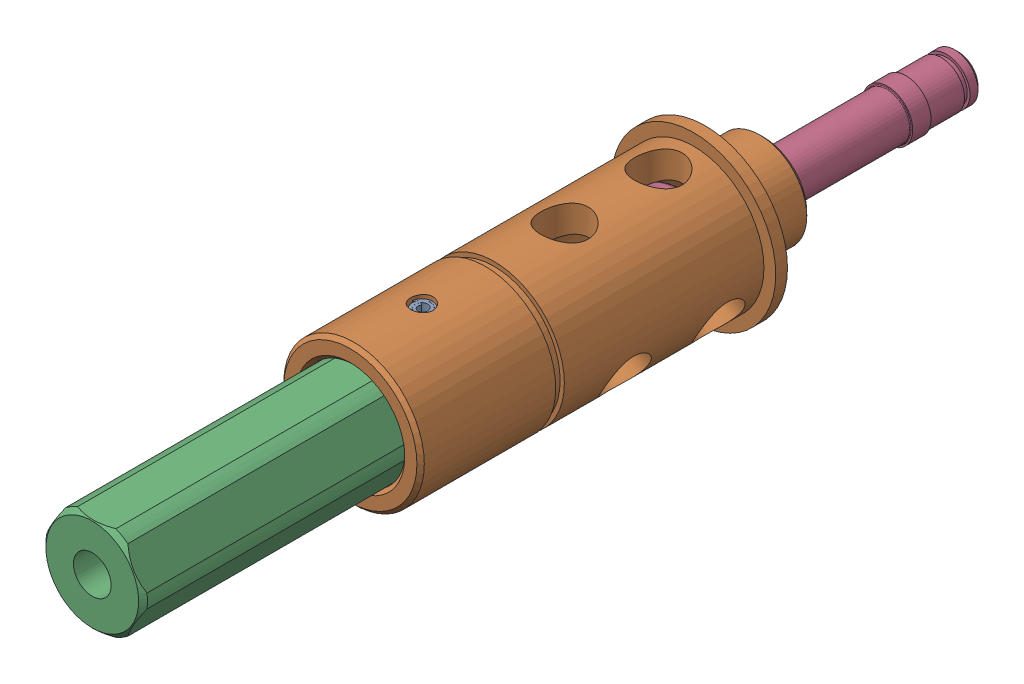
SolidWorks assembly 217-4098-000 Rev2, configuration Default. Lengths in mm.
Overall size (22.23 22.23 117.22).
4 component instances, 4 part files, 0 mates.
Components (placement in the parent):
- 217-4098-005 Rev1_91612A226-1: 217-4098-005 Rev1_91612A226 [Default] at (0 0 46.2661) x (-0.144757 0 0.989467) z (0 -1 0) size (3.02 3.15 18.22)
- 217-4098-003 Rev2-1: 217-4098-003 Rev2 [Default] x (1 0 0) z (0 0 -1) size (22.23 22.23 55.94)
- 217-4098-002 Rev3-1: 217-4098-002 Rev3 [Default] at (0 0 62.9285) x (0 0 1) z (-1 0 0) size (59.88 12.73 14.67)
- 217-4098-004 Rev1-1: 217-4098-004 Rev1 [Default] at (0 0 14.2494) x (-0.610335 0.792144 0) z (0 0 1) size (11.68 11.68 56)
